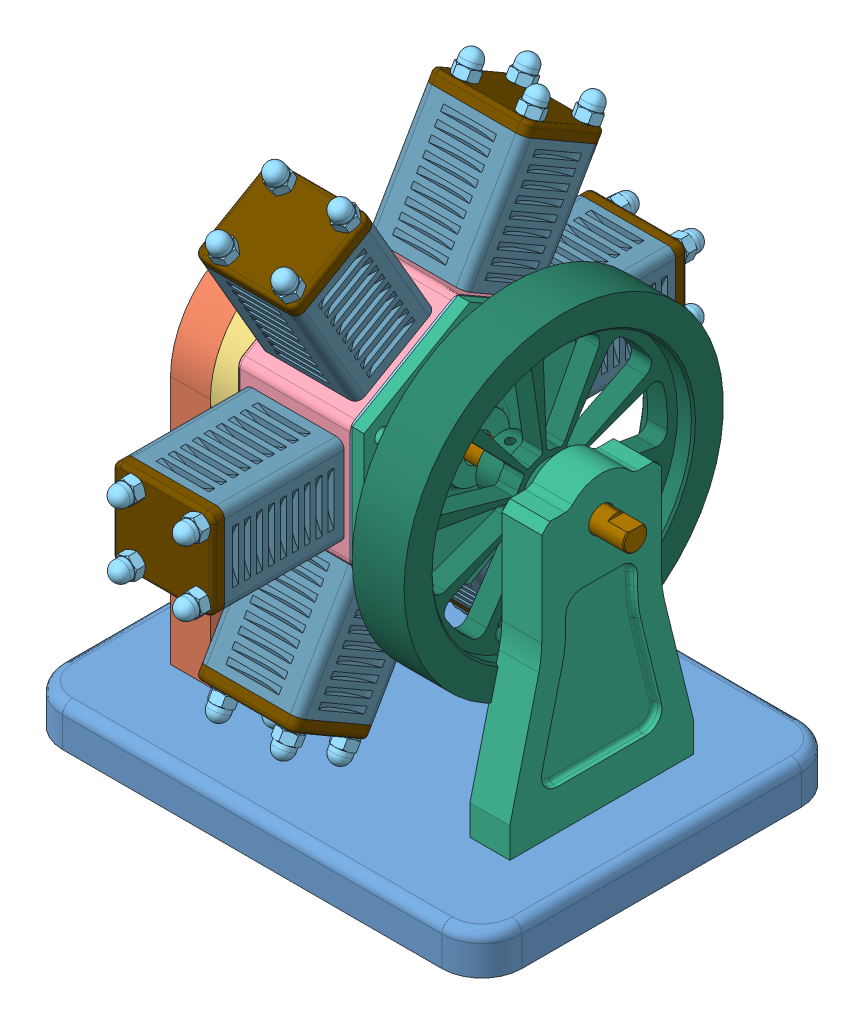
SolidWorks assembly final, configuration Default. Lengths in mm.
Overall size (230 270.67 262.56).
131 component instances, 25 part files, 171 mates.
Components (placement in the parent):
- base-1: base [Default] at (78.5026 100.4112 186.9559) size (230 20 180)
- pillar support-1: pillar support [Default] at (3.5026 245.4112 186.9559) x (0 0 -1) z (1 0 0) size (92 171 20)
- valvehouse-1: valvehouse [Default] at (19.5026 245.4112 186.9559) x (-1 0 0) z (0 0.866025 -0.5) size (30 92 92)
- crankcase-1: crankcase [Default] at (33.5026 245.4112 186.9559) x (0 -0.5 0.866025) z (0 0.866025 0.5) size (120.85 57 106)
- crankcase gasket-1: crankcase gasket [Default] at (91.5026 245.4112 186.9559) x (0 -0.866025 -0.5) z (0 0.5 -0.866025) size (106 1 120.85)
- bearing support-1: bearing support [Default] at (163.5026 134.6094 159.1904) x (0 0 1) z (-1 0 0) size (92 145 20)
- crankshaft-1: crankshaft [Default] at (113.6224 211.2676 180.3455) x (0 0.022213 0.999753) z (-1 0 0) size (64.93 66 135)
  - counter weight-1: counter weight [Default] at (7.3672 33.9883 57.1198) size (64.93 66 12)
  - crantshaft pin-1: crantshaft pin [Default] at (7.3672 51.9883 67.1198) x (0 -1 0) z (1 0 0) size (12 38 12)
  - counter weight-2: counter weight [Default] at (7.3672 33.9883 29.1198) size (64.93 66 12)
  - crankshaft rod-1: crankshaft rod [Default] at (7.3672 33.9883 -66.8802) x (0 -1 0) z (-1 0 0) size (12 106 12)
- VALVE-1: VALVE [Default] at (33.5026 245.4112 186.9559) x (0 0.928426 0.371518) z (0 -0.371518 0.928426) size (42 14 42)
- crankshaft valve crank-1: crankshaft valve crank [Default] at (56.5026 245.4112 186.9559) x (0 -0.999753 0.022213) z (0 -0.022213 -0.999753) size (12 33 12)
- connecting rod hub-1: connecting rod hub [Default] at (57.5026 262.5357 192.4925) x (1 0 0) z (0 -0.989407 -0.145168) size (16 42 42)
- hub pin-1: hub pin [Default] at (73.5026 275.955 196.4828) x (0 1 0) z (0 0 1) size (5 16 5)
- hub pin-2: hub pin [Default] at (73.5026 278.2777 180.6523) x (0 0.987351 0.158553) z (0 -0.158553 0.987351) size (5 16 5)
- hub pin-3: hub pin [Default] at (73.5026 265.7294 170.7255) x (0 0.618657 0.785661) z (0 -0.785661 0.618657) size (5 16 5)
- hub pin-4: hub pin [Default] at (73.5026 261.0841 202.3866) x (0 0.928571 0.371154) z (0 -0.371154 0.928571) size (5 16 5)
- hub pin-5: hub pin [Default] at (73.5026 248.5358 192.4598) x (0 0.906989 0.421154) z (0 -0.421154 0.906989) size (5 16 5)
- hub pin-8: hub pin [Default] at (73.5026 250.8585 176.6293) x (0 0.902849 0.429957) z (0 -0.429957 0.902849) size (5 16 5)
- CYLINDER BODY-1: CYLINDER BODY [Default] at (62.5026 291.3105 213.4559) x (1 0 0) z (0 -0.5 0.866025) size (50 62 45)
- CYLINDER BODY-2: CYLINDER BODY [Default] at (62.5026 291.3105 160.4559) x (1 0 0) z (0 0.5 0.866025) size (50 62 45)
- CYLINDER BODY-3: CYLINDER BODY [Default] at (62.5026 245.4112 133.9559) x (1 0 0) z (0 1 0) size (50 62 45)
- CYLINDER BODY-4: CYLINDER BODY [Default] at (62.5026 245.4112 239.9559) x (1 0 0) z (0 -1 0) size (50 62 45)
- CYLINDER BODY-5: CYLINDER BODY [Default] at (62.5026 199.5118 213.4559) x (1 0 0) z (0 -0.5 -0.866025) size (50 62 45)
- CYLINDER BODY-6: CYLINDER BODY [Default] at (62.5026 199.5118 160.4559) x (1 0 0) z (0 0.5 -0.866025) size (50 62 45)
- flywheel-1: flywheel [Default] at (131.5026 245.4112 186.9559) x (0 0.143613 -0.989634) z (0 -0.989634 -0.143613) size (160 36 160)
- radial ball bearing_68_skf-1: radial ball bearing_68_skf [SKF - 6001 - Full,DE,AC,Full_68] at (153.5026 245.4112 186.9559) x (1 0 0) z (0 0.913263 -0.40737) size (8 28 28)
- radial ball bearing_68_skf-3: radial ball bearing_68_skf [SKF - 6001 - Full,DE,AC,Full_68] at (33.5026 245.4112 186.9559) x (-1 0 0) z (0 0.592985 0.805213) size (8 28 28)
- CYLINDER BOLT-1: CYLINDER BOLT [Default] at (81.766 287.0668 192.2263) x (-0.896736 0.221283 -0.383273) z (0.442566 0.448368 -0.776596) size (6.69 82.56 6.69)
- CYLINDER BOLT-2: CYLINDER BOLT [Default] at (81.766 270.8033 220.3954) x (0.545643 -0.419009 0.725745) z (-0.838018 -0.272821 0.47254) size (6.69 82.56 6.69)
- CYLINDER BOLT-3: CYLINDER BOLT [Default] at (49.2391 270.8033 220.3954) x (-0.999451 -0.016567 0.028695) z (-0.033134 0.499725 -0.86555) size (6.69 82.56 6.69)
- CYLINDER BOLT-4: CYLINDER BOLT [Default] at (49.2391 287.0668 192.2263) x (-0.962048 -0.13644 0.236321) z (-0.27288 0.481024 -0.833158) size (6.69 82.56 6.69)
- CYLINDER COVER-1: CYLINDER COVER [Default] at (62.5026 343.2721 243.4559) x (-1 0 0) z (0 0.866025 0.5) size (50 45 8)
- CYLINDER COVER-3: CYLINDER COVER [Default] at (62.5026 245.4112 299.9559) x (-1 0 0) z (0 0 1) size (50 45 8)
- CYLINDER COVER-4: CYLINDER COVER [Default] at (62.5026 343.2721 130.4559) x (-1 0 0) z (0 0.866025 -0.5) size (50 45 8)
- CYLINDER COVER-5: CYLINDER COVER [Default] at (62.5026 245.4112 73.9559) x (-1 0 0) z (0 0 -1) size (50 45 8)
- CYLINDER COVER-6: CYLINDER COVER [Default] at (62.5026 147.5503 130.4559) x (-1 0 0) z (0 -0.866025 -0.5) size (50 45 8)
- CYLINDER COVER-10: CYLINDER COVER [Default] at (62.5026 147.5503 243.4559) x (-1 0 0) z (0 -0.866025 0.5) size (50 45 8)
- CYLINDER BOLT-7: CYLINDER BOLT [Default] at (49.2391 287.0668 181.6854) x (-0.874905 0.242147 0.419411) z (-0.484294 -0.437453 -0.75769) size (6.69 82.56 6.69)
- CYLINDER BOLT-8: CYLINDER BOLT [Default] at (49.2391 270.8033 153.5163) x (-0.707472 0.353371 0.612056) z (-0.706742 -0.353736 -0.612688) size (6.69 82.56 6.69)
- CYLINDER BOLT-9: CYLINDER BOLT [Default] at (81.766 270.8033 153.5163) x (-0.459236 0.444157 0.769303) z (-0.888314 -0.229618 -0.39771) size (6.69 82.56 6.69)
- CYLINDER BOLT-10: CYLINDER BOLT [Default] at (81.766 287.0668 181.6854) x (-0.173744 0.492395 0.852854) z (-0.984791 -0.086872 -0.150466) size (6.69 82.56 6.69)
- CYLINDER BOLT-11: CYLINDER BOLT [Default] at (49.2391 261.6746 148.2459) x (0.567602 0.823303 0) z (-0.823303 0.567602 0) size (6.69 82.56 6.69)
- CYLINDER BOLT-12: CYLINDER BOLT [Default] at (81.766 261.6746 148.2459) x (0.717345 0.696718 0) z (-0.696718 0.717345 0) size (6.69 82.56 6.69)
- CYLINDER BOLT-13: CYLINDER BOLT [Default] at (81.766 229.1477 148.2459) x (0.766939 0.64172 0) z (-0.64172 0.766939 0) size (6.69 82.56 6.69)
- CYLINDER BOLT-14: CYLINDER BOLT [Default] at (49.2391 229.1477 148.2459) x (0.761204 0.648512 0) z (-0.648512 0.761204 0) size (6.69 82.56 6.69)
- CYLINDER BOLT-15: CYLINDER BOLT [Default] at (49.2391 220.0191 153.5163) x (0.962048 -0.13644 0.236321) z (0.27288 0.481024 -0.833158) size (6.69 82.56 6.69)
- CYLINDER BOLT-16: CYLINDER BOLT [Default] at (81.766 220.0191 153.5163) x (0.999682 0.012604 -0.02183) z (-0.025207 0.499841 -0.86575) size (6.69 82.56 6.69)
- CYLINDER BOLT-17: CYLINDER BOLT [Default] at (81.766 203.7556 181.6854) x (0.968586 0.124339 -0.215361) z (-0.248678 0.484293 -0.83882) size (6.69 82.56 6.69)
- CYLINDER BOLT-18: CYLINDER BOLT [Default] at (49.2391 203.7556 181.6854) x (0.910885 0.20633 -0.357374) z (-0.412661 0.455442 -0.788849) size (6.69 82.56 6.69)
- CYLINDER BOLT-19: CYLINDER BOLT [Default] at (81.766 203.7556 192.2263) x (-0.025999 -0.499831 -0.865733) z (-0.999662 0.012999 0.022516) size (6.69 82.56 6.69)
- CYLINDER BOLT-20: CYLINDER BOLT [Default] at (81.766 220.0191 220.3954) x (-0.569024 0.411161 0.712151) z (0.822321 0.284512 0.492789) size (6.69 82.56 6.69)
- CYLINDER BOLT-21: CYLINDER BOLT [Default] at (49.2391 220.0191 220.3954) x (-0.717345 0.348359 0.603375) z (0.696718 0.358673 0.621239) size (6.69 82.56 6.69)
- CYLINDER BOLT-22: CYLINDER BOLT [Default] at (49.2391 203.7556 192.2263) x (-0.896444 0.221578 0.383785) z (0.443156 0.448222 0.776344) size (6.69 82.56 6.69)
- CYLINDER BOLT-23: CYLINDER BOLT [Default] at (81.766 261.6746 225.6659) x (-0.974968 -0.222346 0) z (-0.222346 0.974968 0) size (6.69 82.56 6.69)
- CYLINDER BOLT-24: CYLINDER BOLT [Default] at (49.2391 261.6746 225.6659) x (-0.962048 -0.27288 0) z (-0.27288 0.962048 0) size (6.69 82.56 6.69)
- CYLINDER BOLT-25: CYLINDER BOLT [Default] at (49.2391 229.1477 225.6659) x (-0.932555 -0.361029 0) z (-0.361029 0.932555 0) size (6.69 82.56 6.69)
- CYLINDER BOLT-26: CYLINDER BOLT [Default] at (81.766 229.1477 225.6659) x (-0.878887 -0.47703 0) z (-0.47703 0.878887 0) size (6.69 82.56 6.69)
- connecting rod-1: connecting rod [Default] at (65.5026 301.0767 161.1534) x (0 0.759965 -0.649964) z (0 0.649964 0.759965) size (70 10 10)
- piston assembly-2: piston assembly [Default] at (34.7388 304.3186 148.1399) x (0 -0.5 -0.866025) z (1 0 0) size (44.81 32.07 44.8)
  - PISTON-1: PISTON [Default] at (-4.1619 11.0296 30.7638) size (32 32.07 32)
  - piston pin-1: piston pin [Default] at (-4.1619 20.1796 15.7638) x (-0.346728 0.937966 0) z (0.937966 0.346728 0) size (5 30 5)
  - piston ring-1: piston ring [Default] at (-4.1619 29.6796 30.7638) x (0.80068 0 0.599092) z (-0.599092 0 0.80068) size (32 1.5 31.97)
  - piston ring-2: piston ring [Default] at (-4.1619 25.1796 30.7638) x (0.797377 0 0.603481) z (-0.603481 0 0.797377) size (32 1.5 31.97)
- domed cap nut_din-1: domed cap nut_din [DIN 1587 - M6 --SNU] at (81.766 340.5805 260.6813) x (0 0.866025 0.5) z (0.750364 -0.330513 0.572465) size (12 11.55 10)
- piston assembly-13: piston assembly [Default] at (34.7388 308.6537 218.6633) x (0 0.5 -0.866025) z (1 0 0) size (44.81 32.07 44.8)
  - PISTON-1: PISTON [Default] at (-4.1619 11.0296 30.7638) size (32 32.07 32)
  - piston pin-1: piston pin [Default] at (-4.1619 20.1796 15.7638) x (-0.346728 0.937966 0) z (0.937966 0.346728 0) size (5 30 5)
  - piston ring-1: piston ring [Default] at (-4.1619 29.6796 30.7638) x (0.80068 0 0.599092) z (-0.599092 0 0.80068) size (32 1.5 31.97)
  - piston ring-2: piston ring [Default] at (-4.1619 25.1796 30.7638) x (0.797377 0 0.603481) z (-0.603481 0 0.797377) size (32 1.5 31.97)
- connecting rod-10: connecting rod [Default] at (65.5026 300.0019 214.4201) x (0 0.801564 0.597909) z (0 -0.597909 0.801564) size (70 10 10)
- piston assembly-14: piston assembly [Default] at (34.7388 249.5731 240.1238) x (0 1 0) z (1 0 0) size (44.81 32.07 44.8)
  - PISTON-1: PISTON [Default] at (-4.1619 11.0296 30.7638) size (32 32.07 32)
  - piston pin-1: piston pin [Default] at (-4.1619 20.1796 15.7638) x (-0.346728 0.937966 0) z (0.937966 0.346728 0) size (5 30 5)
  - piston ring-1: piston ring [Default] at (-4.1619 29.6796 30.7638) x (0.80068 0 0.599092) z (-0.599092 0 0.80068) size (32 1.5 31.97)
  - piston ring-2: piston ring [Default] at (-4.1619 25.1796 30.7638) x (0.797377 0 0.603481) z (-0.603481 0 0.797377) size (32 1.5 31.97)
- connecting rod-11: connecting rod [Default] at (65.5026 253.2476 231.345) x (0 -0.261214 0.965281) z (0 -0.965281 -0.261214) size (70 10 10)
- piston assembly-17: piston assembly [Default] at (34.7388 213.2567 210.326) x (0 0.5 0.866025) z (1 0 0) size (44.81 32.07 44.8)
  - PISTON-1: PISTON [Default] at (-4.1619 11.0296 30.7638) size (32 32.07 32)
  - piston pin-1: piston pin [Default] at (-4.1619 20.1796 15.7638) x (-0.346728 0.937966 0) z (0.937966 0.346728 0) size (5 30 5)
  - piston ring-1: piston ring [Default] at (-4.1619 29.6796 30.7638) x (0.80068 0 0.599092) z (-0.599092 0 0.80068) size (32 1.5 31.97)
  - piston ring-2: piston ring [Default] at (-4.1619 25.1796 30.7638) x (0.797377 0 0.603481) z (-0.603481 0 0.797377) size (32 1.5 31.97)
- connecting rod-14: connecting rod [Default] at (65.5026 221.1177 204.6356) x (0 -0.913934 0.405862) z (0 -0.405862 -0.913934) size (70 10 10)
- piston assembly-19: piston assembly [Default] at (34.7388 209.4505 170.9997) x (0 -0.5 0.866025) z (1 0 0) size (44.81 32.07 44.8)
  - PISTON-1: PISTON [Default] at (-4.1619 11.0296 30.7638) size (32 32.07 32)
  - piston pin-1: piston pin [Default] at (-4.1619 20.1796 15.7638) x (-0.346728 0.937966 0) z (0.937966 0.346728 0) size (5 30 5)
  - piston ring-1: piston ring [Default] at (-4.1619 29.6796 30.7638) x (0.80068 0 0.599092) z (-0.599092 0 0.80068) size (32 1.5 31.97)
  - piston ring-2: piston ring [Default] at (-4.1619 25.1796 30.7638) x (0.797377 0 0.603481) z (-0.603481 0 0.797377) size (32 1.5 31.97)
- connecting rod-16: connecting rod [Default] at (65.5026 222.4569 166.9674) x (0 -0.946719 -0.322062) z (0 0.322062 -0.946719) size (70 10 10)
- piston assembly-21: piston assembly [Default] at (34.7388 241.2493 134.4501) x (0 -1 0) z (1 0 0) size (44.81 32.07 44.8)
  - PISTON-1: PISTON [Default] at (-4.1619 11.0296 30.7638) size (32 32.07 32)
  - piston pin-1: piston pin [Default] at (-4.1619 20.1796 15.7638) x (-0.346728 0.937966 0) z (0.937966 0.346728 0) size (5 30 5)
  - piston ring-1: piston ring [Default] at (-4.1619 29.6796 30.7638) x (0.80068 0 0.599092) z (-0.599092 0 0.80068) size (32 1.5 31.97)
  - piston ring-2: piston ring [Default] at (-4.1619 25.1796 30.7638) x (0.797377 0 0.603481) z (-0.603481 0 0.797377) size (32 1.5 31.97)
- connecting rod-18: connecting rod [Default] at (65.5026 255.5703 142.498) x (0 -0.338637 -0.940917) z (0 0.940917 -0.338637) size (70 10 10)
- domed cap nut_din-3: domed cap nut_din [DIN 1587 - M6 --SNU] at (49.1093 340.5156 260.7937) x (0 0.866025 0.5) z (-0.661025 -0.375182 0.649834) size (12 11.55 10)
- domed cap nut_din-4: domed cap nut_din [DIN 1587 - M6 --SNU] at (48.9795 356.8439 232.5122) x (0 0.866025 0.5) z (-0.750364 0.330513 -0.572465) size (12 11.55 10)
- domed cap nut_din-5: domed cap nut_din [DIN 1587 - M6 --SNU] at (81.6362 356.9088 232.3998) x (0 0.866025 0.5) z (0.661025 0.375182 -0.649834) size (12 11.55 10)
- domed cap nut_din-6: domed cap nut_din [DIN 1587 - M6 --SNU] at (81.766 356.8439 141.3996) x (0 0.866025 -0.5) z (0.750364 0.330513 0.572465) size (12 11.55 10)
- domed cap nut_din-7: domed cap nut_din [DIN 1587 - M6 --SNU] at (81.766 261.6746 67.6741) x (0 0 -1) z (0.750364 0.661025 0) size (12 11.55 10)
- domed cap nut_din-8: domed cap nut_din [DIN 1587 - M6 --SNU] at (81.766 150.2419 113.2304) x (0 -0.866025 -0.5) z (0.750364 0.330513 -0.572465) size (12 11.55 10)
- domed cap nut_din-9: domed cap nut_din [DIN 1587 - M6 --SNU] at (81.766 133.9784 232.5122) x (0 -0.866025 0.5) z (0.750364 -0.330513 -0.572465) size (12 11.55 10)
- domed cap nut_din-10: domed cap nut_din [DIN 1587 - M6 --SNU] at (81.766 229.1477 306.2376) x (0 0 1) z (0.750364 -0.661025 0) size (12 11.55 10)
- domed cap nut_din-11: domed cap nut_din [DIN 1587 - M6 --SNU] at (49.1093 356.9088 141.512) x (0 0.866025 -0.5) z (-0.661025 0.375182 0.649834) size (12 11.55 10)
- domed cap nut_din-12: domed cap nut_din [DIN 1587 - M6 --SNU] at (49.1093 261.8044 67.6741) x (0 0 -1) z (-0.661025 0.750364 0) size (12 11.55 10)
- domed cap nut_din-13: domed cap nut_din [DIN 1587 - M6 --SNU] at (49.1093 150.3068 113.118) x (0 -0.866025 -0.5) z (-0.661025 0.375182 -0.649834) size (12 11.55 10)
- domed cap nut_din-14: domed cap nut_din [DIN 1587 - M6 --SNU] at (49.1093 133.9135 232.3998) x (0 -0.866025 0.5) z (-0.661025 -0.375182 -0.649834) size (12 11.55 10)
- domed cap nut_din-15: domed cap nut_din [DIN 1587 - M6 --SNU] at (49.1093 229.0179 306.2376) x (0 0 1) z (-0.661025 -0.750364 0) size (12 11.55 10)
- domed cap nut_din-16: domed cap nut_din [DIN 1587 - M6 --SNU] at (81.6362 340.5156 113.118) x (0 0.866025 -0.5) z (0.661025 -0.375182 -0.649834) size (12 11.55 10)
- domed cap nut_din-17: domed cap nut_din [DIN 1587 - M6 --SNU] at (81.6362 229.0179 67.6741) x (0 0 -1) z (0.661025 -0.750364 0) size (12 11.55 10)
- domed cap nut_din-18: domed cap nut_din [DIN 1587 - M6 --SNU] at (81.6362 133.9135 141.512) x (0 -0.866025 -0.5) z (0.661025 -0.375182 0.649834) size (12 11.55 10)
- domed cap nut_din-19: domed cap nut_din [DIN 1587 - M6 --SNU] at (81.6362 150.3068 260.7937) x (0 -0.866025 0.5) z (0.661025 0.375182 0.649834) size (12 11.55 10)
- domed cap nut_din-20: domed cap nut_din [DIN 1587 - M6 --SNU] at (81.6362 261.8044 306.2376) x (0 0 1) z (0.661025 0.750364 0) size (12 11.55 10)
- domed cap nut_din-21: domed cap nut_din [DIN 1587 - M6 --SNU] at (48.9795 340.5805 113.2304) x (0 0.866025 -0.5) z (-0.750364 -0.330513 -0.572465) size (12 11.55 10)
- domed cap nut_din-22: domed cap nut_din [DIN 1587 - M6 --SNU] at (48.9795 229.1477 67.6741) x (0 0 -1) z (-0.750364 -0.661025 0) size (12 11.55 10)
- domed cap nut_din-23: domed cap nut_din [DIN 1587 - M6 --SNU] at (48.9795 133.9784 141.3996) x (0 -0.866025 -0.5) z (-0.750364 -0.330513 0.572465) size (12 11.55 10)
- domed cap nut_din-24: domed cap nut_din [DIN 1587 - M6 --SNU] at (48.9795 150.2419 260.6813) x (0 -0.866025 0.5) z (-0.750364 0.330513 0.572465) size (12 11.55 10)
- domed cap nut_din-25: domed cap nut_din [DIN 1587 - M6 --SNU] at (48.9795 261.6746 306.2376) x (0 0 1) z (-0.750364 0.661025 0) size (12 11.55 10)
- cranlshaft case cover-1: cranlshaft case cover [Default] at (101.5026 245.4112 186.9559) x (-1 0 0) z (0 0 -1) size (16 122.4 106)
- socket head cap screw_iso-7: socket head cap screw_iso [ISO 4762 M6 x 35 --- 24S] at (-6.4974 264.9112 153.1809) size (41 10 10)
- socket head cap screw_iso-8: socket head cap screw_iso [ISO 4762 M6 x 35 --- 24S] at (-6.4974 284.4112 186.9559) x (1 0 0) z (0 -0.866025 0.5) size (41 10 10)
- socket head cap screw_iso-9: socket head cap screw_iso [ISO 4762 M6 x 35 --- 24S] at (-6.4974 264.9112 220.7309) x (1 0 0) z (0 -0.866025 -0.5) size (41 10 10)
- socket head cap screw_iso-10: socket head cap screw_iso [ISO 4762 M6 x 35 --- 24S] at (-6.4974 225.9112 220.7309) x (1 0 0) z (0 0 -1) size (41 10 10)
- socket head cap screw_iso-11: socket head cap screw_iso [ISO 4762 M6 x 35 --- 24S] at (-6.4974 206.4112 186.9559) x (1 0 0) z (0 0.866025 -0.5) size (41 10 10)
- socket head cap screw_iso-12: socket head cap screw_iso [ISO 4762 M6 x 35 --- 24S] at (-6.4974 225.9112 153.1809) x (1 0 0) z (0 0.866025 0.5) size (41 10 10)
- socket head cap screw_iso-14: socket head cap screw_iso [ISO 4762 M10 x 35 --- 35S] at (-6.4974 245.4112 186.9559) x (1 0 0) z (0 -0.887553 -0.460706) size (45 16 16)
- socket head cap screw_iso-16: socket head cap screw_iso [ISO 4762 M10 x 35 --- 35S] at (3.5026 100.4112 216.9559) x (0 1 0) z (-0.531682 0 -0.846944) size (45 16 16)
- socket head cap screw_iso-17: socket head cap screw_iso [ISO 4762 M10 x 35 --- 35S] at (3.5026 100.4112 156.9559) x (0 1 0) z (-0.681766 0 -0.731571) size (45 16 16)
- socket head cap screw_iso-18: socket head cap screw_iso [ISO 4762 M10 x 35 --- 35S] at (153.5026 100.4112 216.9559) x (0 1 0) z (-0.823443 0 -0.567399) size (45 16 16)
- socket head cap screw_iso-19: socket head cap screw_iso [ISO 4762 M10 x 35 --- 35S] at (153.5026 100.4112 156.9559) x (0 1 0) z (-0.933512 0 -0.358547) size (45 16 16)
Mates (geometry in assembly coordinates):
- Coincident1: coincident anti-aligned: plane of base-1 through (-16.4974 120.4112 256.9559) normal (0 1 0); plane of pillar support-1 through (13.5026 120.4112 232.9559) normal (0 -1 0)
- Concentric1: concentric aligned: cylinder of base-1 through (3.5026 120.4112 216.9559) axis (0 -1 0) radius 5.5; cylinder of pillar support-1 through (3.5026 120.4112 216.9559) axis (0 -1 0) radius 4.4
- Concentric2: concentric aligned: circle of base-1; cylinder of pillar support-1 through (3.5026 120.4112 156.9559) axis (0 -1 0) radius 4.4
- Concentric3: concentric anti-aligned: cylinder of pillar support-1 through (3.5026 245.4112 186.9559) axis (1 0 0) radius 12.5; cylinder of valvehouse-1 through (13.5026 245.4112 186.9559) axis (-1 0 0) radius 7
- Coincident3: coincident anti-aligned: plane of pillar support-1 through (13.5026 245.4112 186.9559) normal (1 0 0); plane of valvehouse-1 through (13.5026 222.4112 147.1187) normal (-1 0 0)
- Concentric4: concentric anti-aligned: cylinder of valvehouse-1 through (13.5026 245.4112 186.9559) axis (-1 0 0) radius 33; cylinder of crankcase-1 through (45.5026 245.4112 186.9559) axis (1 0 0) radius 45
- Concentric5: concentric aligned: cylinder of crankcase-1 through (90.5026 219.9112 231.1232) axis (1 0 0) radius 2.5; cylinder of crankcase gasket-1 through (90.5026 219.9112 231.1232) axis (1 0 0) radius 3.5
- Coincident6: coincident anti-aligned: plane of crankcase-1 through (90.5026 245.4112 186.9559) normal (1 0 0); plane of crankcase gasket-1 through (90.5026 273.124 234.9559) normal (-1 0 0)
- Concentric6: concentric aligned: cylinder of crankcase-1 through (90.5026 270.9112 142.7886) axis (1 0 0) radius 2.5; cylinder of crankcase gasket-1 through (90.5026 270.9112 142.7886) axis (1 0 0) radius 3.5
- Concentric7: concentric aligned: cylinder of base-1 through (153.5026 120.4112 156.9559) axis (0 -1 0) radius 5.5; cylinder of bearing support-1 through (153.5026 120.4112 156.9559) axis (0 -1 0) radius 4.4
- Concentric8: concentric aligned: cylinder of base-1 through (153.5026 111.4112 216.9559) axis (0 -1 0) radius 9; cylinder of bearing support-1 through (153.5026 120.4112 216.9559) axis (0 -1 0) radius 4.4
- Coincident7: coincident anti-aligned: plane of base-1 through (-16.4974 120.4112 256.9559) normal (0 1 0); plane of bearing support-1 through (143.5026 120.4112 140.9559) normal (0 -1 0)
- Concentric24: concentric aligned: cylinder of pillar support-1 through (13.5026 284.4112 186.9559) axis (-1 0 0) radius 3.5; cylinder of valvehouse-1 through (33.5026 284.4112 186.9559) axis (-1 0 0) radius 3.5
- Concentric25: concentric anti-aligned: cylinder of crankshaft-1/counter weight-1 through (51.5026 244.69 154.4976) axis (0 0.022213 0.999753) radius 1.5; cylinder of crankshaft valve crank-1 through (51.5026 245.5445 192.9544) axis (0 -0.022213 -0.999753) radius 1.149
- Concentric26: concentric aligned: cylinder of crankshaft-1/counter weight-1 through (46.5026 245.4112 186.9559) axis (1 0 0) radius 6; cylinder of crankshaft valve crank-1 through (33.5026 245.4112 186.9559) axis (1 0 0) radius 6
- Concentric28: concentric anti-aligned: cylinder of pillar support-1 through (13.5026 245.4112 186.9559) axis (-1 0 0) radius 8; cylinder of crankcase-1 through (33.5026 245.4112 186.9559) axis (1 0 0) radius 9.5
- Coincident12: coincident anti-aligned: plane of valvehouse-1 through (19.5026 245.4112 186.9559) normal (1 0 0); plane of VALVE-1 through (19.5026 245.4112 186.9559) normal (-1 0 0)
- Concentric29: concentric aligned: cylinder of pillar support-1 through (13.5026 245.4112 186.9559) axis (-1 0 0) radius 8; cylinder of VALVE-1 through (33.5026 245.4112 186.9559) axis (-1 0 0) radius 2
- Concentric31: concentric anti-aligned: cylinder of valvehouse-1 through (33.5026 225.9112 220.7309) axis (-1 0 0) radius 3.5; cylinder of crankcase-1 through (45.5026 225.9112 220.7309) axis (1 0 0) radius 2.5
- Coincident16: coincident anti-aligned: plane of valvehouse-1 through (33.5026 228.9112 158.377) normal (1 0 0); plane of crankcase-1 through (33.5026 245.4112 186.9559) normal (-1 0 0)
- Concentric32: concentric aligned: cylinder of crankshaft-1/crantshaft pin-1 through (84.5026 263.4067 186.556) axis (-1 0 0) radius 6; cylinder of connecting rod hub-1 through (57.5026 263.4067 186.556) axis (-1 0 0) radius 6
- Width1: width aligned: plane of connecting rod hub-1 through (73.5026 262.5357 192.4925) normal (1 0 0); plane of connecting rod hub-1 through (57.5026 260.4308 206.8389) normal (-1 0 0); plane of crankshaft-1/counter weight-1 through (56.5026 269.6642 180.4155) normal (1 0 0); plane of crankshaft-1/counter weight-2 through (74.5026 269.6642 180.4155) normal (-1 0 0)
- Concentric33: concentric anti-aligned: cylinder of connecting rod hub-1 through (73.5026 275.955 196.4828) axis (-1 0 0) radius 2.5; cylinder of hub pin-1 through (57.5026 275.955 196.4828) axis (1 0 0) radius 2.5
- Width2: width aligned: plane of hub pin-1 through (73.5026 275.955 196.4828) normal (1 0 0); plane of hub pin-1 through (57.5026 275.955 196.4828) normal (-1 0 0); plane of connecting rod hub-1 through (73.5026 262.5357 192.4925) normal (1 0 0); plane of connecting rod hub-1 through (57.5026 260.4308 206.8389) normal (-1 0 0)
- Concentric34: concentric anti-aligned: cylinder of connecting rod hub-1 through (73.5026 278.2777 180.6523) axis (-1 0 0) radius 2.5; cylinder of hub pin-2 through (57.5026 278.2777 180.6523) axis (1 0 0) radius 2.5
- Width3: width anti-aligned: plane of hub pin-2 through (73.5026 278.2777 180.6523) normal (1 0 0); plane of hub pin-2 through (57.5026 278.2777 180.6523) normal (-1 0 0); plane of connecting rod hub-1 through (57.5026 260.4308 206.8389) normal (-1 0 0); plane of connecting rod hub-1 through (73.5026 262.5357 192.4925) normal (1 0 0)
- Concentric35: concentric anti-aligned: cylinder of connecting rod hub-1 through (73.5026 265.7294 170.7255) axis (-1 0 0) radius 2.5; cylinder of hub pin-3 through (57.5026 265.7294 170.7255) axis (1 0 0) radius 2.5
- Width4: width anti-aligned: plane of hub pin-3 through (73.5026 265.7294 170.7255) normal (1 0 0); plane of hub pin-3 through (57.5026 265.7294 170.7255) normal (-1 0 0); plane of connecting rod hub-1 through (57.5026 260.4308 206.8389) normal (-1 0 0); plane of connecting rod hub-1 through (73.5026 262.5357 192.4925) normal (1 0 0)
- Concentric36: concentric anti-aligned: cylinder of connecting rod hub-1 through (73.5026 261.0841 202.3866) axis (-1 0 0) radius 2.5; cylinder of hub pin-4 through (57.5026 261.0841 202.3866) axis (1 0 0) radius 2.5
- Width5: width anti-aligned: plane of hub pin-4 through (73.5026 261.0841 202.3866) normal (1 0 0); plane of hub pin-4 through (57.5026 261.0841 202.3866) normal (-1 0 0); plane of connecting rod hub-1 through (57.5026 260.4308 206.8389) normal (-1 0 0); plane of connecting rod hub-1 through (73.5026 262.5357 192.4925) normal (1 0 0)
- Concentric37: concentric anti-aligned: cylinder of connecting rod hub-1 through (73.5026 248.5358 192.4598) axis (-1 0 0) radius 2.5; cylinder of hub pin-5 through (57.5026 248.5358 192.4598) axis (1 0 0) radius 2.5
- Width6: width anti-aligned: plane of hub pin-5 through (73.5026 248.5358 192.4598) normal (1 0 0); plane of hub pin-5 through (57.5026 248.5358 192.4598) normal (-1 0 0); plane of connecting rod hub-1 through (57.5026 260.4308 206.8389) normal (-1 0 0); plane of connecting rod hub-1 through (73.5026 262.5357 192.4925) normal (1 0 0)
- Concentric40: concentric anti-aligned: cylinder of connecting rod hub-1 through (73.5026 250.8585 176.6293) axis (-1 0 0) radius 2.5; cylinder of hub pin-8 through (57.5026 250.8585 176.6293) axis (1 0 0) radius 2.5
- Width7: width anti-aligned: plane of hub pin-8 through (73.5026 250.8585 176.6293) normal (1 0 0); plane of hub pin-8 through (57.5026 250.8585 176.6293) normal (-1 0 0); plane of connecting rod hub-1 through (57.5026 260.4308 206.8389) normal (-1 0 0); plane of connecting rod hub-1 through (73.5026 262.5357 192.4925) normal (1 0 0)
- Concentric47: concentric anti-aligned: cylinder of crankcase-1 through (41.5026 291.3105 213.4559) axis (0 0.866025 0.5) radius 1.65; cylinder of CYLINDER BODY-1 through (41.5026 343.2721 243.4559) axis (0 -0.866025 -0.5) radius 2
- Concentric48: concentric anti-aligned: cylinder of crankcase-1 through (49.2391 283.1788 227.5404) axis (0 0.866025 0.5) radius 2.5; cylinder of CYLINDER BODY-1 through (49.2391 335.1403 257.5404) axis (0 -0.866025 -0.5) radius 3.5
- Coincident19: coincident anti-aligned: plane of crankcase-1 through (90.5026 306.6103 186.9559) normal (0 0.866025 0.5); plane of CYLINDER BODY-1 through (41.5026 282.0605 229.4773) normal (0 -0.866025 -0.5)
- Concentric49: concentric anti-aligned: cylinder of crankcase-1 through (41.5026 291.3105 160.4559) axis (0 0.866025 -0.5) radius 1.65; cylinder of CYLINDER BODY-2 through (41.5026 343.2721 130.4559) axis (0 -0.866025 0.5) radius 2
- Concentric50: concentric anti-aligned: cylinder of crankcase-1 through (49.2391 299.4423 174.5404) axis (0 0.866025 -0.5) radius 2.5; cylinder of CYLINDER BODY-2 through (49.2391 351.4038 144.5404) axis (0 -0.866025 0.5) radius 3.5
- Coincident20: coincident anti-aligned: plane of crankcase-1 through (90.5026 276.0108 133.9559) normal (0 0.866025 -0.5); plane of CYLINDER BODY-2 through (41.5026 300.5605 176.4773) normal (0 -0.866025 0.5)
- Concentric51: concentric anti-aligned: cylinder of crankcase-1 through (41.5026 245.4112 133.9559) axis (0 0 -1) radius 1.65; cylinder of CYLINDER BODY-3 through (41.5026 245.4112 73.9559) axis (0 0 1) radius 2
- Concentric52: concentric anti-aligned: cylinder of crankcase-1 through (49.2391 261.6746 133.9559) axis (0 0 -1) radius 2.5; cylinder of CYLINDER BODY-3 through (49.2391 261.6746 73.9559) axis (0 0 1) radius 3.5
- Coincident21: coincident anti-aligned: plane of crankcase-1 through (90.5026 214.8116 133.9559) normal (0 0 -1); plane of CYLINDER BODY-3 through (41.5026 263.9112 133.9559) normal (0 0 1)
- Concentric53: concentric anti-aligned: cylinder of crankcase-1 through (41.5026 245.4112 239.9559) axis (0 0 1) radius 1.65; cylinder of CYLINDER BODY-4 through (41.5026 245.4112 299.9559) axis (0 0 -1) radius 2
- Concentric54: concentric anti-aligned: cylinder of crankcase-1 through (49.2391 229.1477 239.9559) axis (0 0 1) radius 2.5; cylinder of CYLINDER BODY-4 through (49.2391 229.1477 299.9559) axis (0 0 -1) radius 3.5
- Coincident22: coincident anti-aligned: plane of crankcase-1 through (90.5026 276.0108 239.9559) normal (0 0 1); plane of CYLINDER BODY-4 through (41.5026 226.9112 239.9559) normal (0 0 -1)
- Concentric55: concentric anti-aligned: cylinder of crankcase-1 through (41.5026 199.5118 213.4559) axis (0 -0.866025 0.5) radius 1.65; cylinder of CYLINDER BODY-5 through (41.5026 147.5503 243.4559) axis (0 0.866025 -0.5) radius 2
- Concentric56: concentric anti-aligned: cylinder of crankcase-1 through (49.2391 191.3801 199.3713) axis (0 -0.866025 0.5) radius 2.5; cylinder of CYLINDER BODY-5 through (49.2391 139.4186 229.3713) axis (0 0.866025 -0.5) radius 3.5
- Coincident23: coincident anti-aligned: plane of crankcase-1 through (90.5026 214.8116 239.9559) normal (0 -0.866025 0.5); plane of CYLINDER BODY-5 through (41.5026 190.2618 197.4344) normal (0 0.866025 -0.5)
- Concentric57: concentric anti-aligned: cylinder of crankcase-1 through (41.5026 199.5118 160.4559) axis (0 -0.866025 -0.5) radius 1.65; cylinder of CYLINDER BODY-6 through (41.5026 147.5503 130.4559) axis (0 0.866025 0.5) radius 2
- Concentric58: concentric anti-aligned: cylinder of crankcase-1 through (49.2391 207.6436 146.3713) axis (0 -0.866025 -0.5) radius 2.5; cylinder of CYLINDER BODY-6 through (49.2391 155.682 116.3713) axis (0 0.866025 0.5) radius 3.5
- Coincident24: coincident anti-aligned: plane of crankcase-1 through (90.5026 184.2121 186.9559) normal (0 -0.866025 -0.5); plane of CYLINDER BODY-6 through (41.5026 208.7618 144.4344) normal (0 0.866025 0.5)
- Concentric59: concentric anti-aligned: cylinder of crankshaft-1/crankshaft rod-1 through (74.5026 245.4112 186.9559) axis (1 0 0) radius 6; cylinder of flywheel-1 through (149.5026 245.4112 186.9559) axis (-1 0 0) radius 6
- Concentric60: concentric anti-aligned: cylinder of bearing support-1 through (157.5026 245.4112 186.9559) axis (-1 0 0) radius 15; cylinder of radial ball bearing_68_skf-1 through (132.8651 245.4112 186.9559) axis (1 0 0) radius 6
- Coincident25: coincident anti-aligned: plane of bearing support-1 through (157.5026 245.4112 186.9559) normal (-1 0 0); plane of radial ball bearing_68_skf-1 through (157.5026 242.8448 181.2023) normal (1 0 0)
- Coincident27: coincident anti-aligned: plane of VALVE-1 through (29.5026 245.4112 186.9559) normal (1 0 0); plane of radial ball bearing_68_skf-3 through (29.5026 234.3798 195.0798) normal (-1 0 0)
- Concentric61: concentric anti-aligned: cylinder of crankcase-1 through (37.5026 245.4112 186.9559) axis (1 0 0) radius 14; cylinder of radial ball bearing_68_skf-3 through (54.1401 245.4112 186.9559) axis (-1 0 0) radius 14
- Concentric62: concentric aligned: cylinder of CYLINDER BODY-1 through (81.766 351.4038 229.3713) axis (0 -0.866025 -0.5) radius 3.5; cylinder of CYLINDER BOLT-1 through (81.766 358.0808 233.2263) axis (0 -0.866025 -0.5) radius 3
- Distance1: distance = 7.71 mm aligned: plane of CYLINDER BOLT-1 through (81.766 358.0808 233.2263) normal (0 0.866025 0.5); plane of CYLINDER BODY-1 through (41.5026 334.0221 259.4773) normal (0 0.866025 0.5)
- Concentric63: concentric aligned: cylinder of CYLINDER BODY-1 through (81.766 335.1403 257.5404) axis (0 -0.866025 -0.5) radius 3.5; cylinder of CYLINDER BOLT-2 through (81.766 341.8174 261.3954) axis (0 -0.866025 -0.5) radius 3
- Distance2: distance = 7.71 mm aligned: plane of CYLINDER BOLT-2 through (81.766 341.8174 261.3954) normal (0 0.866025 0.5); plane of CYLINDER BODY-1 through (41.5026 334.0221 259.4773) normal (0 0.866025 0.5)
- Concentric64: concentric aligned: cylinder of CYLINDER BODY-1 through (49.2391 335.1403 257.5404) axis (0 -0.866025 -0.5) radius 3.5; cylinder of CYLINDER BOLT-3 through (49.2391 341.8174 261.3954) axis (0 -0.866025 -0.5) radius 3
- Distance3: distance = 7.71 mm aligned: plane of CYLINDER BOLT-3 through (49.2391 341.8174 261.3954) normal (0 0.866025 0.5); plane of CYLINDER BODY-1 through (41.5026 334.0221 259.4773) normal (0 0.866025 0.5)
- Concentric65: concentric aligned: cylinder of CYLINDER BODY-1 through (49.2391 351.4038 229.3713) axis (0 -0.866025 -0.5) radius 3.5; cylinder of CYLINDER BOLT-4 through (49.2391 358.0808 233.2263) axis (0 -0.866025 -0.5) radius 3
- Distance4: distance = 7.71 mm aligned: plane of CYLINDER BOLT-4 through (49.2391 358.0808 233.2263) normal (0 0.866025 0.5); plane of CYLINDER BODY-1 through (41.5026 334.0221 259.4773) normal (0 0.866025 0.5)
- Concentric68: concentric aligned: cylinder of CYLINDER BODY-1 through (81.766 335.1403 257.5404) axis (0 -0.866025 -0.5) radius 3.5; cylinder of CYLINDER COVER-1 through (81.766 340.3365 260.5404) axis (0 -0.866025 -0.5) radius 2.6273
- Concentric69: concentric aligned: cylinder of CYLINDER BODY-1 through (49.2391 351.4038 229.3713) axis (0 -0.866025 -0.5) radius 3.5; cylinder of CYLINDER COVER-1 through (49.2391 356.5999 232.3713) axis (0 -0.866025 -0.5) radius 2.6273
- Coincident29: coincident anti-aligned: plane of CYLINDER BODY-1 through (41.5026 334.0221 259.4773) normal (0 0.866025 0.5); plane of CYLINDER COVER-1 through (41.5026 334.0221 259.4773) normal (0 -0.866025 -0.5)
- Concentric72: concentric aligned: cylinder of CYLINDER BODY-4 through (81.766 229.1477 299.9559) axis (0 0 -1) radius 3.5; cylinder of CYLINDER COVER-3 through (81.766 229.1477 305.9559) axis (0 0 -1) radius 2.6273
- Concentric76: concentric aligned: cylinder of CYLINDER BODY-4 through (49.2391 261.6746 299.9559) axis (0 0 -1) radius 3.5; cylinder of CYLINDER COVER-3 through (49.2391 261.6746 305.9559) axis (0 0 -1) radius 2.6273
- Coincident30: coincident anti-aligned: plane of CYLINDER BODY-4 through (41.5026 226.9112 299.9559) normal (0 0 1); plane of CYLINDER COVER-3 through (41.5026 226.9112 299.9559) normal (0 0 -1)
- Concentric77: concentric aligned: cylinder of CYLINDER BODY-2 through (81.766 351.4038 144.5404) axis (0 -0.866025 0.5) radius 3.5; cylinder of CYLINDER COVER-4 through (81.766 356.5999 141.5404) axis (0 -0.866025 0.5) radius 2.6273
- Concentric78: concentric aligned: cylinder of CYLINDER BODY-2 through (49.2391 335.1403 116.3713) axis (0 -0.866025 0.5) radius 3.5; cylinder of CYLINDER COVER-4 through (49.2391 340.3365 113.3713) axis (0 -0.866025 0.5) radius 2.6273
- Coincident31: coincident anti-aligned: plane of CYLINDER BODY-2 through (41.5026 352.5221 146.4773) normal (0 0.866025 -0.5); plane of CYLINDER COVER-4 through (41.5026 352.5221 146.4773) normal (0 -0.866025 0.5)
- Concentric79: concentric aligned: cylinder of CYLINDER BODY-3 through (81.766 261.6746 73.9559) axis (0 0 1) radius 3.5; cylinder of CYLINDER COVER-5 through (81.766 261.6746 67.9559) axis (0 0 1) radius 2.6273
- Concentric80: concentric aligned: cylinder of CYLINDER BODY-3 through (49.2391 229.1477 73.9559) axis (0 0 1) radius 3.5; cylinder of CYLINDER COVER-5 through (49.2391 229.1477 67.9559) axis (0 0 1) radius 2.6273
- Coincident32: coincident anti-aligned: plane of CYLINDER BODY-3 through (41.5026 263.9112 73.9559) normal (0 0 -1); plane of CYLINDER COVER-5 through (41.5026 263.9112 73.9559) normal (0 0 1)
- Concentric81: concentric aligned: cylinder of CYLINDER BODY-6 through (81.766 155.682 116.3713) axis (0 0.866025 0.5) radius 3.5; cylinder of CYLINDER COVER-6 through (81.766 150.4859 113.3713) axis (0 0.866025 0.5) radius 2.6273
- Concentric82: concentric aligned: cylinder of CYLINDER BODY-6 through (49.2391 139.4186 144.5404) axis (0 0.866025 0.5) radius 3.5; cylinder of CYLINDER COVER-6 through (49.2391 134.2224 141.5404) axis (0 0.866025 0.5) radius 2.6273
- Coincident33: coincident anti-aligned: plane of CYLINDER BODY-6 through (41.5026 156.8003 114.4344) normal (0 -0.866025 -0.5); plane of CYLINDER COVER-6 through (41.5026 156.8003 114.4344) normal (0 0.866025 0.5)
- Concentric85: concentric aligned: cylinder of CYLINDER BODY-5 through (81.766 139.4186 229.3713) axis (0 0.866025 -0.5) radius 3.5; cylinder of CYLINDER COVER-10 through (81.766 134.2224 232.3713) axis (0 0.866025 -0.5) radius 2.6273
- Concentric86: concentric aligned: cylinder of CYLINDER BODY-5 through (49.2391 155.682 257.5404) axis (0 0.866025 -0.5) radius 3.5; cylinder of CYLINDER COVER-10 through (49.2391 150.4859 260.5404) axis (0 0.866025 -0.5) radius 2.6273
- Coincident35: coincident anti-aligned: plane of CYLINDER BODY-5 through (41.5026 138.3003 227.4344) normal (0 -0.866025 0.5); plane of CYLINDER COVER-10 through (41.5026 138.3003 227.4344) normal (0 0.866025 -0.5)
- Concentric89: concentric aligned: cylinder of CYLINDER BODY-2 through (49.2391 351.4038 144.5404) axis (0 -0.866025 0.5) radius 3.5; cylinder of CYLINDER BOLT-7 through (49.2391 358.0808 140.6854) axis (0 -0.866025 0.5) radius 3
- Distance7: distance = 7.71 mm aligned: plane of CYLINDER BOLT-7 through (49.2391 358.0808 140.6854) normal (0 0.866025 -0.5); plane of CYLINDER BODY-2 through (41.5026 352.5221 146.4773) normal (0 0.866025 -0.5)
- Concentric90: concentric aligned: cylinder of CYLINDER BODY-2 through (49.2391 335.1403 116.3713) axis (0 -0.866025 0.5) radius 3.5; cylinder of CYLINDER BOLT-8 through (49.2391 341.8174 112.5163) axis (0 -0.866025 0.5) radius 3
- Distance8: distance = 7.71 mm aligned: plane of CYLINDER BOLT-8 through (49.2391 341.8174 112.5163) normal (0 0.866025 -0.5); plane of CYLINDER BODY-2 through (41.5026 352.5221 146.4773) normal (0 0.866025 -0.5)
- Concentric91: concentric aligned: cylinder of CYLINDER BODY-2 through (81.766 335.1403 116.3713) axis (0 -0.866025 0.5) radius 3.5; cylinder of CYLINDER BOLT-9 through (81.766 341.8174 112.5163) axis (0 -0.866025 0.5) radius 3
- Distance9: distance = 7.71 mm aligned: plane of CYLINDER BOLT-9 through (81.766 341.8174 112.5163) normal (0 0.866025 -0.5); plane of CYLINDER BODY-2 through (41.5026 352.5221 146.4773) normal (0 0.866025 -0.5)
- Concentric92: concentric aligned: cylinder of CYLINDER BODY-2 through (81.766 351.4038 144.5404) axis (0 -0.866025 0.5) radius 3.5; cylinder of CYLINDER BOLT-10 through (81.766 358.0808 140.6854) axis (0 -0.866025 0.5) radius 3
- Distance10: distance = 7.71 mm aligned: plane of CYLINDER BOLT-10 through (81.766 358.0808 140.6854) normal (0 0.866025 -0.5); plane of CYLINDER BODY-2 through (41.5026 352.5221 146.4773) normal (0 0.866025 -0.5)
- Concentric93: concentric aligned: cylinder of CYLINDER BODY-3 through (49.2391 261.6746 73.9559) axis (0 0 1) radius 3.5; cylinder of CYLINDER BOLT-11 through (49.2391 261.6746 66.2459) axis (0 0 1) radius 3
- Distance11: distance = 7.71 mm aligned: plane of CYLINDER BOLT-11 through (49.2391 261.6746 66.2459) normal (0 0 -1); plane of CYLINDER BODY-3 through (41.5026 263.9112 73.9559) normal (0 0 -1)
- Concentric94: concentric aligned: cylinder of CYLINDER BODY-3 through (81.766 261.6746 73.9559) axis (0 0 1) radius 3.5; cylinder of CYLINDER BOLT-12 through (81.766 261.6746 66.2459) axis (0 0 1) radius 3
- Distance12: distance = 7.71 mm aligned: plane of CYLINDER BOLT-12 through (81.766 261.6746 66.2459) normal (0 0 -1); plane of CYLINDER BODY-3 through (41.5026 263.9112 73.9559) normal (0 0 -1)
- Concentric95: concentric aligned: cylinder of CYLINDER BODY-3 through (81.766 229.1477 73.9559) axis (0 0 1) radius 3.5; cylinder of CYLINDER BOLT-13 through (81.766 229.1477 66.2459) axis (0 0 1) radius 3
- Distance13: distance = 7.71 mm aligned: plane of CYLINDER BOLT-13 through (81.766 229.1477 66.2459) normal (0 0 -1); plane of CYLINDER BODY-3 through (41.5026 263.9112 73.9559) normal (0 0 -1)
- Concentric96: concentric aligned: cylinder of CYLINDER BODY-3 through (49.2391 229.1477 73.9559) axis (0 0 1) radius 3.5; cylinder of CYLINDER BOLT-14 through (49.2391 229.1477 66.2459) axis (0 0 1) radius 3
- Distance14: distance = 7.71 mm aligned: plane of CYLINDER BOLT-14 through (49.2391 229.1477 66.2459) normal (0 0 -1); plane of CYLINDER BODY-3 through (41.5026 263.9112 73.9559) normal (0 0 -1)
- Concentric97: concentric aligned: cylinder of CYLINDER BODY-6 through (49.2391 155.682 116.3713) axis (0 0.866025 0.5) radius 3.5; cylinder of CYLINDER BOLT-15 through (49.2391 149.005 112.5163) axis (0 0.866025 0.5) radius 3
- Distance15: distance = 7.71 mm aligned: plane of CYLINDER BOLT-15 through (49.2391 149.005 112.5163) normal (0 -0.866025 -0.5); plane of CYLINDER BODY-6 through (41.5026 156.8003 114.4344) normal (0 -0.866025 -0.5)
- Concentric98: concentric aligned: cylinder of CYLINDER BODY-6 through (81.766 155.682 116.3713) axis (0 0.866025 0.5) radius 3.5; cylinder of CYLINDER BOLT-16 through (81.766 149.005 112.5163) axis (0 0.866025 0.5) radius 3
- Distance16: distance = 7.71 mm aligned: plane of CYLINDER BOLT-16 through (81.766 149.005 112.5163) normal (0 -0.866025 -0.5); plane of CYLINDER BODY-6 through (41.5026 156.8003 114.4344) normal (0 -0.866025 -0.5)
- Concentric99: concentric aligned: cylinder of CYLINDER BODY-6 through (81.766 139.4186 144.5404) axis (0 0.866025 0.5) radius 3.5; cylinder of CYLINDER BOLT-17 through (81.766 132.7415 140.6854) axis (0 0.866025 0.5) radius 3
- Distance17: distance = 7.71 mm aligned: plane of CYLINDER BOLT-17 through (81.766 132.7415 140.6854) normal (0 -0.866025 -0.5); plane of CYLINDER BODY-6 through (41.5026 156.8003 114.4344) normal (0 -0.866025 -0.5)
- Concentric100: concentric aligned: cylinder of CYLINDER BODY-6 through (49.2391 139.4186 144.5404) axis (0 0.866025 0.5) radius 3.5; cylinder of CYLINDER BOLT-18 through (49.2391 132.7415 140.6854) axis (0 0.866025 0.5) radius 3
- Distance18: distance = 7.71 mm aligned: plane of CYLINDER BOLT-18 through (49.2391 132.7415 140.6854) normal (0 -0.866025 -0.5); plane of CYLINDER BODY-6 through (41.5026 156.8003 114.4344) normal (0 -0.866025 -0.5)
- Concentric101: concentric aligned: cylinder of CYLINDER BODY-5 through (81.766 139.4186 229.3713) axis (0 0.866025 -0.5) radius 3.5; cylinder of CYLINDER BOLT-19 through (81.766 132.7415 233.2263) axis (0 0.866025 -0.5) radius 3
- Distance19: distance = 7.71 mm aligned: plane of CYLINDER BOLT-19 through (81.766 132.7415 233.2263) normal (0 -0.866025 0.5); plane of CYLINDER BODY-5 through (41.5026 138.3003 227.4344) normal (0 -0.866025 0.5)
- Concentric102: concentric aligned: cylinder of CYLINDER BODY-5 through (81.766 155.682 257.5404) axis (0 0.866025 -0.5) radius 3.5; cylinder of CYLINDER BOLT-20 through (81.766 149.005 261.3954) axis (0 0.866025 -0.5) radius 3
- Distance20: distance = 7.71 mm aligned: plane of CYLINDER BOLT-20 through (81.766 149.005 261.3954) normal (0 -0.866025 0.5); plane of CYLINDER BODY-5 through (41.5026 138.3003 227.4344) normal (0 -0.866025 0.5)
- Concentric103: concentric aligned: cylinder of CYLINDER BODY-5 through (49.2391 155.682 257.5404) axis (0 0.866025 -0.5) radius 3.5; cylinder of CYLINDER BOLT-21 through (49.2391 149.005 261.3954) axis (0 0.866025 -0.5) radius 3
- Distance21: distance = 7.71 mm aligned: plane of CYLINDER BOLT-21 through (49.2391 149.005 261.3954) normal (0 -0.866025 0.5); plane of CYLINDER BODY-5 through (41.5026 138.3003 227.4344) normal (0 -0.866025 0.5)
- Concentric104: concentric aligned: cylinder of CYLINDER BODY-5 through (49.2391 139.4186 229.3713) axis (0 0.866025 -0.5) radius 3.5; cylinder of CYLINDER BOLT-22 through (49.2391 132.7415 233.2263) axis (0 0.866025 -0.5) radius 3
- Distance22: distance = 7.71 mm aligned: plane of CYLINDER BOLT-22 through (49.2391 132.7415 233.2263) normal (0 -0.866025 0.5); plane of CYLINDER BODY-5 through (41.5026 138.3003 227.4344) normal (0 -0.866025 0.5)
- Concentric105: concentric aligned: cylinder of CYLINDER BODY-4 through (81.766 261.6746 299.9559) axis (0 0 -1) radius 3.5; cylinder of CYLINDER BOLT-23 through (81.766 261.6746 307.6659) axis (0 0 -1) radius 3
- Distance23: distance = 7.71 mm aligned: plane of CYLINDER BOLT-23 through (81.766 261.6746 307.6659) normal (0 0 1); plane of CYLINDER BODY-4 through (41.5026 226.9112 299.9559) normal (0 0 1)
- Concentric106: concentric aligned: cylinder of CYLINDER BODY-4 through (49.2391 261.6746 299.9559) axis (0 0 -1) radius 3.5; cylinder of CYLINDER BOLT-24 through (49.2391 261.6746 307.6659) axis (0 0 -1) radius 3
- Distance24: distance = 7.71 mm aligned: plane of CYLINDER BOLT-24 through (49.2391 261.6746 307.6659) normal (0 0 1); plane of CYLINDER BODY-4 through (41.5026 226.9112 299.9559) normal (0 0 1)
- Concentric107: concentric aligned: cylinder of CYLINDER BODY-4 through (49.2391 229.1477 299.9559) axis (0 0 -1) radius 3.5; cylinder of CYLINDER BOLT-25 through (49.2391 229.1477 307.6659) axis (0 0 -1) radius 3
- Distance25: distance = 7.71 mm aligned: plane of CYLINDER BOLT-25 through (49.2391 229.1477 307.6659) normal (0 0 1); plane of CYLINDER BODY-4 through (41.5026 226.9112 299.9559) normal (0 0 1)
- Concentric108: concentric aligned: cylinder of CYLINDER BODY-4 through (81.766 229.1477 299.9559) axis (0 0 -1) radius 3.5; cylinder of CYLINDER BOLT-26 through (81.766 229.1477 307.6659) axis (0 0 -1) radius 3
- Distance26: distance = 7.71 mm aligned: plane of CYLINDER BOLT-26 through (81.766 229.1477 307.6659) normal (0 0 1); plane of CYLINDER BODY-4 through (41.5026 226.9112 299.9559) normal (0 0 1)
- Concentric125: concentric aligned: cylinder of connecting rod-1 through (70.5026 323.8756 141.6544) axis (-1 0 0) radius 2.5; cylinder of piston assembly-2/piston pin-1 through (80.5026 323.8756 141.6544) axis (-1 0 0) radius 2.5
- Width9: width: plane of connecting rod-1 through (70.5026 323.8756 141.6544) normal (1 0 0); plane of connecting rod-1 through (60.5026 323.8756 141.6544) normal (-1 0 0); cylinder of piston assembly-2/PISTON-1 through (65.5026 337.732 133.6544) axis (0 0.866025 -0.5) radius 16
- Concentric126: concentric anti-aligned: cylinder of CYLINDER BODY-2 through (65.5026 343.2721 130.4559) axis (0 -0.866025 0.5) radius 16; cylinder of piston assembly-2/PISTON-1 through (65.5026 337.732 133.6544) axis (0 0.866025 -0.5) radius 16
- Concentric127: concentric anti-aligned: cylinder of hub pin-2 through (57.5026 278.2777 180.6523) axis (1 0 0) radius 2.5; cylinder of connecting rod-1 through (70.5026 278.2777 180.6523) axis (-1 0 0) radius 2.5
- Coincident41: coincident anti-aligned: plane of flywheel-1 through (149.5026 245.4112 186.9559) normal (1 0 0); plane of radial ball bearing_68_skf-1 through (149.5026 240.6857 176.362) normal (-1 0 0)
- Universal Joint1: universal joint: cylinder of crankshaft-1/crankshaft rod-1 through (74.5026 245.4112 186.9559) axis (1 0 0) radius 6; cylinder of flywheel-1 through (149.5026 245.4112 186.9559) axis (-1 0 0) radius 13
- Parallel2: parallel anti-aligned: plane of CYLINDER COVER-1 through (41.5026 339.2182 262.4773) normal (0 0.866025 0.5); plane of domed cap nut_din-1 through (77.9496 338.4144 264.4331) normal (0 -0.866025 -0.5)
- Concentric137: concentric aligned: cylinder of CYLINDER BOLT-2 through (81.766 341.8174 261.3954) axis (0 -0.866025 -0.5) radius 3; cylinder of domed cap nut_din-1 through (81.766 340.5805 260.6813) axis (0 -0.866025 -0.5) radius 2.5
- Concentric138: concentric aligned: cylinder of piston assembly-13/piston pin-1 through (80.5026 324.0489 232.3574) axis (-1 0 0) radius 2.5; cylinder of connecting rod-10 through (70.5026 324.0489 232.3574) axis (-1 0 0) radius 2.5
- Width13: width: plane of connecting rod-10 through (70.5026 324.0489 232.3574) normal (1 0 0); plane of connecting rod-10 through (60.5026 324.0489 232.3574) normal (-1 0 0); cylinder of piston assembly-13/PISTON-1 through (65.5026 337.9053 240.3574) axis (0 0.866025 0.5) radius 16
- Concentric139: concentric anti-aligned: cylinder of CYLINDER BODY-1 through (65.5026 343.2721 243.4559) axis (0 -0.866025 -0.5) radius 16; cylinder of piston assembly-13/PISTON-1 through (65.5026 337.9053 240.3574) axis (0 0.866025 0.5) radius 16
- Concentric140: concentric anti-aligned: cylinder of hub pin-1 through (57.5026 275.955 196.4828) axis (1 0 0) radius 2.5; cylinder of connecting rod-10 through (70.5026 275.955 196.4828) axis (-1 0 0) radius 2.5
- Concentric141: concentric aligned: cylinder of piston assembly-14/piston pin-1 through (80.5026 245.4112 260.3034) axis (-1 0 0) radius 2.5; cylinder of connecting rod-11 through (70.5026 245.4112 260.3034) axis (-1 0 0) radius 2.5
- Width14: width: plane of connecting rod-11 through (70.5026 245.4112 260.3034) normal (1 0 0); plane of connecting rod-11 through (60.5026 245.4112 260.3034) normal (-1 0 0); cylinder of piston assembly-14/PISTON-1 through (65.5026 245.4112 276.3034) axis (0 0 1) radius 16
- Concentric142: concentric anti-aligned: cylinder of CYLINDER BODY-4 through (65.5026 245.4112 299.9559) axis (0 0 -1) radius 16; cylinder of piston assembly-14/PISTON-1 through (65.5026 245.4112 276.3034) axis (0 0 1) radius 16
- Concentric143: concentric anti-aligned: cylinder of hub pin-4 through (57.5026 261.0841 202.3866) axis (1 0 0) radius 2.5; cylinder of connecting rod-11 through (70.5026 261.0841 202.3866) axis (-1 0 0) radius 2.5
- Concentric149: concentric aligned: cylinder of piston assembly-17/piston pin-1 through (80.5026 193.6997 216.8115) axis (-1 0 0) radius 2.5; cylinder of connecting rod-14 through (70.5026 193.6997 216.8115) axis (-1 0 0) radius 2.5
- Width17: width: plane of connecting rod-14 through (70.5026 193.6997 216.8115) normal (1 0 0); plane of connecting rod-14 through (60.5026 193.6997 216.8115) normal (-1 0 0); cylinder of piston assembly-17/PISTON-1 through (65.5026 179.8433 224.8115) axis (0 -0.866025 0.5) radius 16
- Concentric150: concentric anti-aligned: cylinder of hub pin-5 through (57.5026 248.5358 192.4598) axis (1 0 0) radius 2.5; cylinder of connecting rod-14 through (70.5026 248.5358 192.4598) axis (-1 0 0) radius 2.5
- Concentric152: concentric anti-aligned: cylinder of CYLINDER BODY-5 through (65.5026 147.5503 243.4559) axis (0 0.866025 -0.5) radius 16; cylinder of piston assembly-17/PISTON-1 through (65.5026 179.8433 224.8115) axis (0 -0.866025 0.5) radius 16
- Concentric156: concentric aligned: cylinder of piston assembly-19/piston pin-1 through (80.5026 194.0553 157.3056) axis (-1 0 0) radius 2.5; cylinder of connecting rod-16 through (70.5026 194.0553 157.3056) axis (-1 0 0) radius 2.5
- Width19: width: plane of connecting rod-16 through (70.5026 194.0553 157.3056) normal (1 0 0); plane of connecting rod-16 through (60.5026 194.0553 157.3056) normal (-1 0 0); cylinder of piston assembly-19/PISTON-1 through (65.5026 180.1989 149.3056) axis (0 -0.866025 -0.5) radius 16
- Concentric157: concentric anti-aligned: cylinder of hub pin-8 through (57.5026 250.8585 176.6293) axis (1 0 0) radius 2.5; cylinder of connecting rod-16 through (70.5026 250.8585 176.6293) axis (-1 0 0) radius 2.5
- Concentric158: concentric anti-aligned: cylinder of CYLINDER BODY-6 through (65.5026 147.5503 130.4559) axis (0 0.866025 0.5) radius 16; cylinder of piston assembly-19/PISTON-1 through (65.5026 180.1989 149.3056) axis (0 -0.866025 -0.5) radius 16
- Concentric162: concentric aligned: cylinder of piston assembly-21/piston pin-1 through (80.5026 245.4112 114.2705) axis (-1 0 0) radius 2.5; cylinder of connecting rod-18 through (70.5026 245.4112 114.2705) axis (-1 0 0) radius 2.5
- Width21: width: plane of connecting rod-18 through (70.5026 245.4112 114.2705) normal (1 0 0); plane of connecting rod-18 through (60.5026 245.4112 114.2705) normal (-1 0 0); cylinder of piston assembly-21/PISTON-1 through (65.5026 245.4112 98.2705) axis (0 0 -1) radius 16
- Concentric163: concentric anti-aligned: cylinder of hub pin-3 through (57.5026 265.7294 170.7255) axis (1 0 0) radius 2.5; cylinder of connecting rod-18 through (70.5026 265.7294 170.7255) axis (-1 0 0) radius 2.5
- Concentric164: concentric anti-aligned: cylinder of CYLINDER BODY-3 through (65.5026 245.4112 73.9559) axis (0 0 1) radius 16; cylinder of piston assembly-21/PISTON-1 through (65.5026 245.4112 98.2705) axis (0 0 -1) radius 16
- Concentric165: concentric aligned: cylinder of bearing support-1 through (143.5026 245.4112 186.9559) axis (1 0 0) radius 6.5; cylinder of crankshaft-1/crankshaft rod-1 through (74.5026 245.4112 186.9559) axis (1 0 0) radius 6
- Screw2: screw = 2 mm aligned: cylinder of CYLINDER BODY-1 through (81.766 335.1403 257.5404) axis (0 -0.866025 -0.5) radius 3.5; cylinder of domed cap nut_din-1 through (81.766 340.5805 260.6813) axis (0 -0.866025 -0.5) radius 2.5
- LimitDistance1: limit distance = 0.2818 mm anti-aligned: plane of domed cap nut_din-1 through (77.9496 338.4144 264.4331) normal (0 -0.866025 -0.5); plane of CYLINDER COVER-1 through (41.5026 339.2182 262.4773) normal (0 0.866025 0.5)
- Concentric166: concentric anti-aligned: cylinder of VALVE-1 through (33.5026 245.4112 186.9559) axis (-1 0 0) radius 2; cylinder of crankshaft valve crank-1 through (23.5026 245.4112 186.9559) axis (1 0 0) radius 2
- Coincident43: coincident anti-aligned: plane of VALVE-1 through (33.5026 245.4112 186.9559) normal (1 0 0); plane of crankshaft valve crank-1 through (33.5026 245.4112 186.9559) normal (-1 0 0)
- Concentric168: concentric anti-aligned: cylinder of crankcase-1 through (90.5026 296.4112 186.9559) axis (1 0 0) radius 2.5; cylinder of cranlshaft case cover-1 through (101.5026 296.4112 186.9559) axis (-1 0 0) radius 3.5
- Concentric169: concentric anti-aligned: cylinder of crankcase gasket-1 through (90.5026 194.4112 186.9559) axis (1 0 0) radius 3.5; cylinder of cranlshaft case cover-1 through (101.5026 194.4112 186.9559) axis (-1 0 0) radius 3.5
- Coincident44: coincident anti-aligned: plane of crankcase gasket-1 through (91.5026 273.124 234.9559) normal (1 0 0); plane of cranlshaft case cover-1 through (91.5026 290.4112 186.9559) normal (-1 0 0)
- Concentric171: concentric aligned: cylinder of pillar support-1 through (13.5026 264.9112 153.1809) axis (-1 0 0) radius 3.5; cylinder of socket head cap screw_iso-7 through (-38.2474 264.9112 153.1809) axis (-1 0 0) radius 3
- Coincident46: coincident anti-aligned: plane of pillar support-1 through (-0.4974 264.9112 153.1809) normal (-1 0 0); plane of socket head cap screw_iso-7 through (-0.4974 269.9112 153.1809) normal (1 0 0)
- Concentric172: concentric aligned: cylinder of pillar support-1 through (13.5026 245.4112 186.9559) axis (-1 0 0) radius 8; cylinder of socket head cap screw_iso-14 through (-38.2474 245.4112 186.9559) axis (-1 0 0) radius 5
- Coincident47: coincident aligned: plane of pillar support-1 through (-6.4974 245.4112 186.9559) normal (-1 0 0); plane of socket head cap screw_iso-14 through (-6.4974 245.4112 186.9559) normal (-1 0 0)
- Concentric177: concentric aligned: cylinder of base-1 through (3.5026 111.4112 216.9559) axis (0 -1 0) radius 9; cylinder of socket head cap screw_iso-16 through (3.5026 68.6612 216.9559) axis (0 -1 0) radius 5
- Coincident49: coincident aligned: plane of base-1 through (-16.4974 100.4112 256.9559) normal (0 -1 0); plane of socket head cap screw_iso-16 through (3.5026 100.4112 216.9559) normal (0 -1 0)
- Concentric178: concentric aligned: cylinder of base-1 through (3.5026 111.4112 156.9559) axis (0 -1 0) radius 9; cylinder of socket head cap screw_iso-17 through (3.5026 68.6612 156.9559) axis (0 -1 0) radius 5
- Coincident51: coincident aligned: plane of base-1 through (-16.4974 100.4112 256.9559) normal (0 -1 0); plane of socket head cap screw_iso-17 through (3.5026 100.4112 156.9559) normal (0 -1 0)
- Concentric179: concentric aligned: cylinder of base-1 through (153.5026 111.4112 216.9559) axis (0 -1 0) radius 9; cylinder of socket head cap screw_iso-18 through (153.5026 68.6612 216.9559) axis (0 -1 0) radius 5
- Coincident52: coincident aligned: plane of base-1 through (-16.4974 100.4112 256.9559) normal (0 -1 0); plane of socket head cap screw_iso-18 through (153.5026 100.4112 216.9559) normal (0 -1 0)
- Concentric180: concentric aligned: cylinder of base-1 through (153.5026 111.4112 156.9559) axis (0 -1 0) radius 9; cylinder of socket head cap screw_iso-19 through (153.5026 68.6612 156.9559) axis (0 -1 0) radius 5
- Coincident53: coincident aligned: plane of base-1 through (-16.4974 100.4112 256.9559) normal (0 -1 0); plane of socket head cap screw_iso-19 through (153.5026 100.4112 156.9559) normal (0 -1 0)
